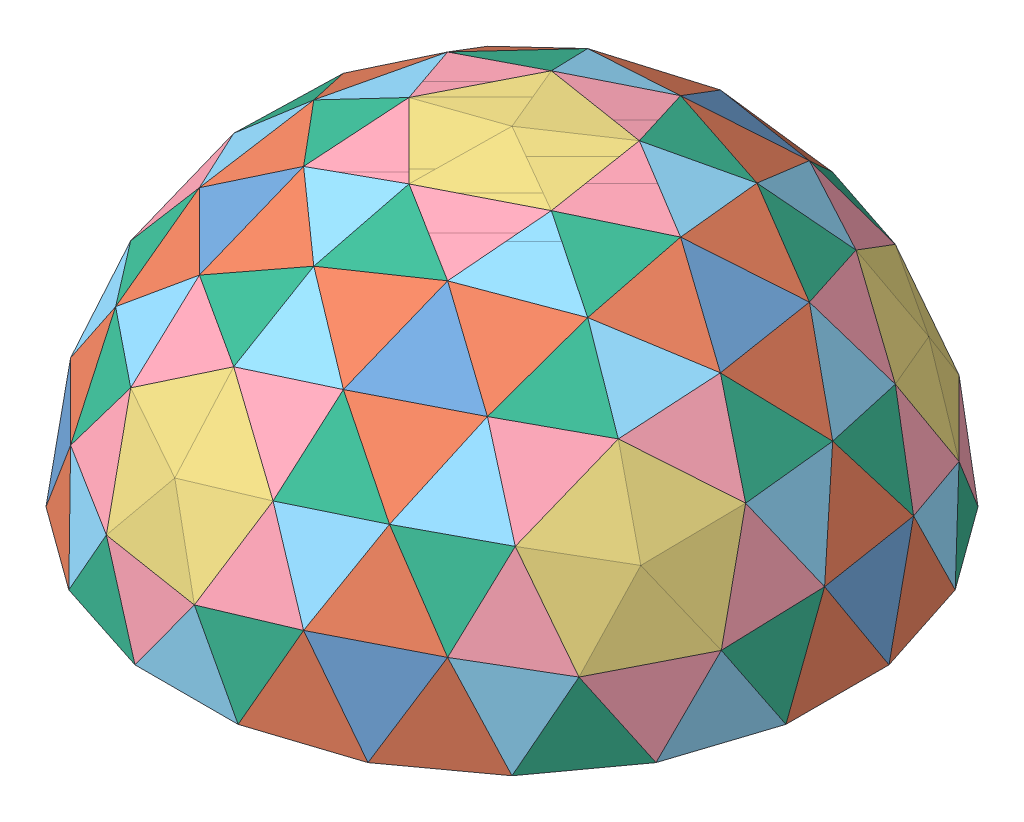
SolidWorks assembly 4Vcorrection, configuration Default. Lengths in mm.
Overall size (6859.98 6146.13 6920.15).
240 component instances, 6 part files, 18 mates.
Components (placement in the parent):
- CCC-1: CCC [Default] at (5148.8544 1241.364 -148.3819) x (0.61992 0.559911 0.549726) z (-0.217119 -0.550832 0.805881) size (730.63 724.53 798.79)
- AAC-1: AAC [Default] at (1003.1437 19.7447 -1471.5178) x (-0.000489 -0.000047 -1) z (0.99533 0.09653 -0.000491) size (938.61 833.05 70.45)
- FFE-1: FFE [Default] at (-5600.516 7252.777 -2822.5483) x (0.186193 0.133009 -0.973469) z (0.267365 0.946545 0.180468) size (827.29 778.64 221.61)
- BBE-1: BBE [Default] at (-5187.0728 4686.9327 1618.959) x (-0.998714 -0.045499 -0.022385) z (0.046496 -0.997846 -0.046278) size (848.33 839.56 282.37)
- ABD-2: ABD [Default] at (-8587.5048 5777.0189 2775.2885) x (-0.624268 -0.021342 0.780919) z (0.059066 -0.998055 0.019942) size (875.61 757.03 437.85)
- ABD_MIRROR-1: ABD_MIRROR [Default] at (1402.3648 4874.5263 -349.4587) x (0.99908 -0.011123 -0.041412) z (0.039506 0.61429 0.788091) size (875.59 747.16 437.21)
- CCC-31: CCC [Default] at (1449.9639 1241.364 -4942.7041) x (0.714386 0.559911 -0.419705) z (0.699345 -0.550832 0.455523) size (730.63 724.53 798.79)
- CCC-32: CCC [Default] at (-4252.7274 1241.364 -2906.3772) x (-0.178406 0.559911 -0.809117) z (0.649338 -0.550832 -0.524352) size (730.63 724.53 798.79)
- CCC-33: CCC [Default] at (-4078.294 1241.364 3146.4642) x (-0.824647 0.559911 -0.080357) z (-0.298032 -0.550832 -0.779591) size (730.63 724.53 798.79)
- CCC-34: CCC [Default] at (1732.2031 1241.364 4850.999) x (-0.331254 0.559911 0.759454) z (-0.833532 -0.550832 0.042538) size (730.63 724.53 798.79)
- AAC-101: AAC [Default] at (1485.5308 -774.2041 604.8619) x (0.385614 -0.797118 0.464656) z (0.921236 0.360604 -0.145909) size (938.61 833.05 70.45)
- AAC-130: AAC [Default] at (1012.6606 1431.4903 312.0988) x (0.060682 0.883368 0.464735) z (0.946767 0.09653 -0.307106) size (938.61 833.05 70.45)
- AAC-131: AAC [Default] at (1611.8244 210.7493 -727.7764) x (0.701451 -0.406472 -0.585445) z (0.543824 0.836189 0.07102) size (938.61 833.05 70.45)
- CCC-26: CCC [Default] at (3250.1059 4014.1834 -1181.8827) x (0.626993 0.22033 -0.747217) z (-0.756223 -0.058225 -0.651719) size (730.63 724.53 798.79)
- AAC-104: AAC [Default] at (-207.4568 1573.9434 -807.289) x (-0.649291 0.632125 -0.422893) z (0.730552 0.672982 -0.115708) size (938.61 833.05 70.45)
- AAC-140: AAC [Default] at (759.5765 1083.2561 1192.3303) x (0.223363 0.139508 0.9647) z (0.495261 0.836189 -0.235595) size (938.61 833.05 70.45)
- AAC-136: AAC [Default] at (609.753 1431.4903 -866.6536) x (0.460741 0.883368 0.085899) z (0.000491 0.09653 -0.99533) size (938.61 833.05 70.45)
- AAC-137: AAC [Default] at (-635.8125 1431.4903 -847.7202) x (0.224072 0.883368 -0.411646) z (-0.946463 0.09653 -0.308041) size (938.61 833.05 70.45)
- AAC-138: AAC [Default] at (-1002.7067 1431.4903 342.7337) x (-0.322257 0.883368 -0.340311) z (-0.585438 0.09653 0.80495) size (938.61 833.05 70.45)
- AAC-139: AAC [Default] at (16.1057 1431.4903 1059.5413) x (-0.423238 0.883368 0.201323) z (0.584643 0.09653 0.805528) size (938.61 833.05 70.45)
- AAC-126: AAC [Default] at (1034.3121 -774.2041 -1225.9111) x (0.561075 -0.797118 -0.223154) z (0.145909 0.360604 -0.921236) size (938.61 833.05 70.45)
- AAC-127: AAC [Default] at (-846.2907 -774.2041 -1362.5167) x (-0.03885 -0.797118 -0.602573) z (-0.831059 0.360604 -0.423446) size (938.61 833.05 70.45)
- AAC-128: AAC [Default] at (-1557.3486 -774.2041 383.8295) x (-0.585086 -0.797118 -0.149256) z (-0.659532 0.360604 0.659532) size (938.61 833.05 70.45)
- AAC-129: AAC [Default] at (-116.2036 -774.2041 1599.7364) x (-0.322753 -0.797118 0.510327) z (0.423446 0.360604 0.831059) size (938.61 833.05 70.45)
- AAC-145: AAC [Default] at (-1089.5081 19.7447 -1408.7704) x (-0.951208 -0.000047 -0.308552) z (0.307106 0.09653 -0.946767) size (938.61 833.05 70.45)
- AAC-146: AAC [Default] at (-1676.4968 19.7447 600.8498) x (-0.587389 -0.000047 0.809304) z (-0.805528 0.09653 -0.584643) size (938.61 833.05 70.45)
- AAC-147: AAC [Default] at (53.3761 19.7447 1780.116) x (0.588181 -0.000047 0.808729) z (-0.80495 0.09653 0.585438) size (938.61 833.05 70.45)
- AAC-148: AAC [Default] at (1709.485 19.7447 499.3224) x (0.950905 -0.000047 -0.309482) z (0.308041 0.09653 0.946463) size (938.61 833.05 70.45)
- AAC-132: AAC [Default] at (-194.0754 210.7493 -1757.8314) x (-0.340031 -0.406472 -0.848032) z (0.235595 0.836189 -0.495261) size (938.61 833.05 70.45)
- AAC-133: AAC [Default] at (-1731.7696 210.7493 -358.6231) x (-0.911602 -0.406472 0.061332) z (-0.398218 0.836189 -0.377108) size (938.61 833.05 70.45)
- AAC-134: AAC [Default] at (-876.2171 210.7493 1536.1901) x (-0.22337 -0.406472 0.885938) z (-0.481707 0.836189 0.262195) size (938.61 833.05 70.45)
- AAC-135: AAC [Default] at (1190.2376 210.7493 1308.0408) x (0.773552 -0.406472 0.486207) z (0.100507 0.836189 0.539154) size (938.61 833.05 70.45)
- CCC-27: CCC [Default] at (-119.6993 4014.1834 -3456.2562) x (-0.516894 0.22033 -0.827209) z (-0.853507 -0.058225 0.517818) size (730.63 724.53 798.79)
- CCC-28: CCC [Default] at (-3324.0841 4014.1834 -954.2011) x (-0.946452 0.22033 0.235974) z (0.228726 -0.058225 0.971748) size (730.63 724.53 798.79)
- CCC-29: CCC [Default] at (-1934.6977 4014.1834 2866.5275) x (-0.068045 0.22033 0.973049) z (0.994868 -0.058225 0.082755) size (730.63 724.53 798.79)
- CCC-30: CCC [Default] at (2128.3752 4014.1834 2725.8125) x (0.904398 0.22033 0.365403) z (0.386136 -0.058225 -0.920603) size (730.63 724.53 798.79)
- AAC-122: AAC [Default] at (-831.8851 1573.9434 -52.1629) x (-0.602838 0.632125 0.486832) z (0.115708 0.672982 -0.730552) size (938.61 833.05 70.45)
- AAC-123: AAC [Default] at (-306.6765 1573.9434 775.0505) x (0.276717 0.632125 0.723772) z (-0.659041 0.672982 -0.335798) size (938.61 833.05 70.45)
- AAC-124: AAC [Default] at (642.3486 1573.9434 531.1705) x (0.773858 0.632125 -0.039516) z (-0.523018 0.672982 0.523018) size (938.61 833.05 70.45)
- AAC-125: AAC [Default] at (703.6698 1573.9434 -446.7691) x (0.201554 0.632125 -0.748194) z (0.335798 0.672982 0.659041) size (938.61 833.05 70.45)
- AAC-141: AAC [Default] at (1368.6955 1083.2561 -353.9498) x (0.986507 0.139508 0.085677) z (-0.07102 0.836189 -0.543824) size (938.61 833.05 70.45)
- AAC-142: AAC [Default] at (86.3239 1083.2561 -1411.0833) x (0.386332 0.139508 -0.911748) z (-0.539154 0.836189 -0.100507) size (938.61 833.05 70.45)
- AAC-143: AAC [Default] at (-1315.3444 1083.2561 -518.1476) x (-0.747741 0.139508 -0.649169) z (-0.262195 0.836189 0.481707) size (938.61 833.05 70.45)
- AAC-144: AAC [Default] at (-899.2515 1083.2561 1090.8505) x (-0.848461 0.139508 0.51054) z (0.377108 0.836189 0.398218) size (938.61 833.05 70.45)
- ABD-53: ABD [Default] at (-14.2287 5777.0189 9024.8137) x (0.549789 -0.021342 0.835031) z (0.037218 -0.998055 -0.050013) size (875.61 757.03 437.85)
- ABD-114: ABD [Default] at (8578.711 5777.0189 2802.3531) x (0.964056 -0.021342 -0.264841) z (-0.036064 -0.998055 -0.050851) size (875.61 757.03 437.85)
- ABD-124: ABD [Default] at (5316.1637 5777.0189 -7292.8643) x (0.04603 -0.021342 -0.998712) z (-0.059507 -0.998055 0.018585) size (875.61 757.03 437.85)
- ABD-134: ABD [Default] at (-5293.1411 5777.0189 -7309.5911) x (-0.935607 -0.021342 -0.352396) z (-0.000713 -0.998055 0.062338) size (875.61 757.03 437.85)
- ABD_MIRROR-37: ABD_MIRROR [Default] at (100.9996 4874.5263 -1441.7169) x (0.269347 -0.011123 -0.962979) z (0.761727 0.61429 0.205961) size (875.59 747.16 437.21)
- ABD_MIRROR-98: ABD_MIRROR [Default] at (-1339.9436 4874.5263 -541.5713) x (-0.832614 -0.011123 -0.553741) z (0.431267 0.61429 -0.660799) size (875.59 747.16 437.21)
- ABD_MIRROR-108: ABD_MIRROR [Default] at (-929.1303 4874.5263 1107.0074) x (-0.783931 -0.011123 0.620748) z (-0.495189 0.61429 -0.614358) size (875.59 747.16 437.21)
- ABD_MIRROR-118: ABD_MIRROR [Default] at (765.7096 4874.5263 1225.7395) x (0.348118 -0.011123 0.937385) z (-0.737311 0.61429 0.281105) size (875.59 747.16 437.21)
- BBE-31: BBE [Default] at (-63.1721 4686.9327 5433.4852) x (-0.329909 -0.045499 0.942916) z (-0.029645 -0.997846 -0.058521) size (848.33 839.56 282.37)
- BBE-92: BBE [Default] at (5148.0302 4686.9327 1739.1195) x (0.794819 -0.045499 0.605139) z (-0.064818 -0.997846 0.01011) size (848.33 839.56 282.37)
- BBE-102: BBE [Default] at (3244.8298 4686.9327 -4358.6502) x (0.821134 -0.045499 -0.568919) z (-0.010415 -0.997846 0.064769) size (848.33 839.56 282.37)
- BBE-112: BBE [Default] at (-3142.6151 4686.9327 -4432.9135) x (-0.28733 -0.045499 -0.95675) z (0.058381 -0.997846 0.02992) size (848.33 839.56 282.37)
- FFE-27: FFE [Default] at (-4415.0576 7252.777 4454.1919) x (-0.868287 0.133009 -0.477898) z (0.254256 0.946545 -0.198512) size (827.29 778.64 221.61)
- FFE-88: FFE [Default] at (2871.8604 7252.777 5575.3903) x (-0.722823 0.133009 0.678111) z (-0.110226 0.946545 -0.303155) size (827.29 778.64 221.61)
- FFE-98: FFE [Default] at (6189.9649 7252.777 -1008.4112) x (0.421558 0.133009 0.896994) z (-0.322379 0.946545 0.011151) size (827.29 778.64 221.61)
- FFE-108: FFE [Default] at (953.7484 7252.777 -6198.6227) x (0.98336 0.133009 -0.123739) z (-0.089015 0.946545 0.310047) size (827.29 778.64 221.61)
- ABD-144: ABD [Default] at (7425.9821 6236.8509 4558.2775) x (0.55211 0.767678 -0.325337) z (0.079677 -0.436992 -0.89593) size (875.61 757.03 437.85)
- ABD_MIRROR-128: ABD_MIRROR [Default] at (-2035.5868 1675.0194 4347.465) x (-0.980472 -0.181349 -0.076077) z (-0.192233 0.965403 0.176194) size (875.59 747.16 437.21)
- BBE-122: BBE [Default] at (4322.8362 4252.0445 3837.6158) x (0.993481 0.099616 0.05542) z (0.097703 -0.493639 -0.864161) size (848.33 839.56 282.37)
- FFE-118: FFE [Default] at (4751.0256 1533.678 8186.0199) x (-0.11914 -0.826546 0.550116) z (-0.411602 0.545327 0.730207) size (827.29 778.64 221.61)
- ABD-78: ABD [Default] at (-1565.091 10558.2109 946.6183) x (-0.610686 0.651209 -0.450545) z (0.107204 -0.495733 -0.861833) size (875.61 757.03 437.85)
- ABD-115: ABD [Default] at (-9510.3268 3858.8763 3079.6379) x (-0.925408 -0.378399 0.020829) z (0.179567 -0.48622 -0.855187) size (875.61 757.03 437.85)
- ABD-125: ABD [Default] at (-5429.6796 -4602.9001 8009.5757) x (0.042879 -0.898262 0.437363) z (0.196762 -0.421599 -0.885177) size (875.61 757.03 437.85)
- ABD-135: ABD [Default] at (5037.5349 -3133.231 8923.4252) x (0.956035 -0.189947 0.22342) z (0.135026 -0.391174 -0.910358) size (875.61 757.03 437.85)
- ABD_MIRROR-62: ABD_MIRROR [Default] at (-658.536 892.1879 4961.8632) x (-0.181899 -0.893371 0.410853) z (-0.854964 0.350088 0.382719) size (875.59 747.16 437.21)
- ABD_MIRROR-99: ABD_MIRROR [Default] at (686.0331 1889.006 4670.2003) x (0.870203 -0.377659 0.316419) z (-0.454945 -0.369384 0.810296) size (875.59 747.16 437.21)
- ABD_MIRROR-109: ABD_MIRROR [Default] at (139.9716 3287.9049 3875.5444) x (0.721865 0.653091 -0.228875) z (0.455011 -0.198728 0.868028) size (875.59 747.16 437.21)
- ABD_MIRROR-119: ABD_MIRROR [Default] at (-1542.082 3155.654 3676.083) x (-0.421915 0.774417 -0.471451) z (0.617376 0.626216 0.47613) size (875.59 747.16 437.21)
- BBE-56: BBE [Default] at (-1057.5495 6904.923 1642.4729) x (0.251277 0.858799 -0.446457) z (0.17386 -0.493801 -0.852017) size (848.33 839.56 282.37)
- BBE-93: BBE [Default] at (-5882.7201 2912.1164 2899.5297) x (-0.829386 0.403031 -0.386892) z (0.202695 -0.42825 -0.880634) size (848.33 839.56 282.37)
- BBE-103: BBE [Default] at (-3484.4538 -2208.4524 5871.5765) x (-0.755068 -0.637832 0.151797) z (0.14436 -0.387575 -0.910465) size (848.33 839.56 282.37)
- BBE-113: BBE [Default] at (2822.9269 -1380.3313 6451.3455) x (0.371526 -0.825352 0.425161) z (0.079471 -0.427987 -0.900284) size (848.33 839.56 282.37)
- FFE-52: FFE [Default] at (2960.0958 7796.1933 4732.0753) x (0.878748 -0.241209 0.41185) z (-0.366301 0.212364 0.905939) size (827.29 778.64 221.61)
- FFE-89: FFE [Default] at (-4324.0091 7767.0971 3593.1159) x (0.636517 0.759674 -0.133195) z (0.002188 0.170919 0.985283) size (827.29 778.64 221.61)
- FFE-99: FFE [Default] at (-7034.9037 1486.5995 6343.1447) x (-0.511078 0.792917 -0.331785) z (0.184626 0.478266 0.858589) size (827.29 778.64 221.61)
- FFE-109: FFE [Default] at (-1426.2239 -2365.8654 9181.7155) x (-0.9781 -0.18742 0.090524) z (-0.07111 0.709663 0.700944) size (827.29 778.64 221.61)
- ABD-149: ABD [Default] at (-14.2287 5777.0189 9024.8137) x (0.549789 -0.021342 0.835031) z (0.037218 -0.998055 -0.050013) size (875.61 757.03 437.85)
- ABD-150: ABD [Default] at (8578.711 5777.0189 2802.3531) x (0.964056 -0.021342 -0.264841) z (-0.036064 -0.998055 -0.050851) size (875.61 757.03 437.85)
- ABD-151: ABD [Default] at (5316.1637 5777.0189 -7292.8643) x (0.04603 -0.021342 -0.998712) z (-0.059507 -0.998055 0.018585) size (875.61 757.03 437.85)
- ABD-152: ABD [Default] at (-5293.1411 5777.0189 -7309.5911) x (-0.935607 -0.021342 -0.352396) z (-0.000713 -0.998055 0.062338) size (875.61 757.03 437.85)
- ABD_MIRROR-133: ABD_MIRROR [Default] at (100.9996 4874.5263 -1441.7169) x (0.269347 -0.011123 -0.962979) z (0.761727 0.61429 0.205961) size (875.59 747.16 437.21)
- ABD_MIRROR-134: ABD_MIRROR [Default] at (-1339.9436 4874.5263 -541.5713) x (-0.832614 -0.011123 -0.553741) z (0.431267 0.61429 -0.660799) size (875.59 747.16 437.21)
- ABD_MIRROR-135: ABD_MIRROR [Default] at (-929.1303 4874.5263 1107.0074) x (-0.783931 -0.011123 0.620748) z (-0.495189 0.61429 -0.614358) size (875.59 747.16 437.21)
- ABD_MIRROR-136: ABD_MIRROR [Default] at (765.7096 4874.5263 1225.7395) x (0.348118 -0.011123 0.937385) z (-0.737311 0.61429 0.281105) size (875.59 747.16 437.21)
- BBE-127: BBE [Default] at (-63.1721 4686.9327 5433.4852) x (-0.329909 -0.045499 0.942916) z (-0.029645 -0.997846 -0.058521) size (848.33 839.56 282.37)
- BBE-128: BBE [Default] at (5148.0302 4686.9327 1739.1195) x (0.794819 -0.045499 0.605139) z (-0.064818 -0.997846 0.01011) size (848.33 839.56 282.37)
- BBE-129: BBE [Default] at (3244.8298 4686.9327 -4358.6502) x (0.821134 -0.045499 -0.568919) z (-0.010415 -0.997846 0.064769) size (848.33 839.56 282.37)
- BBE-130: BBE [Default] at (-3142.6151 4686.9327 -4432.9135) x (-0.28733 -0.045499 -0.95675) z (0.058381 -0.997846 0.02992) size (848.33 839.56 282.37)
- FFE-123: FFE [Default] at (-4415.0576 7252.777 4454.1919) x (-0.868287 0.133009 -0.477898) z (0.254256 0.946545 -0.198512) size (827.29 778.64 221.61)
- FFE-124: FFE [Default] at (2871.8604 7252.777 5575.3903) x (-0.722823 0.133009 0.678111) z (-0.110226 0.946545 -0.303155) size (827.29 778.64 221.61)
- FFE-125: FFE [Default] at (6189.9649 7252.777 -1008.4112) x (0.421558 0.133009 0.896994) z (-0.322379 0.946545 0.011151) size (827.29 778.64 221.61)
- FFE-126: FFE [Default] at (953.7484 7252.777 -6198.6227) x (0.98336 0.133009 -0.123739) z (-0.089015 0.946545 0.310047) size (827.29 778.64 221.61)
- ABD-110: ABD [Default] at (8578.711 5777.0189 2802.3531) x (0.964056 -0.021342 -0.264841) z (-0.036064 -0.998055 -0.050851) size (875.61 757.03 437.85)
- ABD-111: ABD [Default] at (5316.1637 5777.0189 -7292.8643) x (0.04603 -0.021342 -0.998712) z (-0.059507 -0.998055 0.018585) size (875.61 757.03 437.85)
- ABD-112: ABD [Default] at (-5293.1411 5777.0189 -7309.5911) x (-0.935607 -0.021342 -0.352396) z (-0.000713 -0.998055 0.062338) size (875.61 757.03 437.85)
- ABD-113: ABD [Default] at (-8587.5048 5777.0189 2775.2885) x (-0.624268 -0.021342 0.780919) z (0.059066 -0.998055 0.019942) size (875.61 757.03 437.85)
- ABD-120: ABD [Default] at (5316.1637 5777.0189 -7292.8643) x (0.04603 -0.021342 -0.998712) z (-0.059507 -0.998055 0.018585) size (875.61 757.03 437.85)
- ABD-121: ABD [Default] at (-5293.1411 5777.0189 -7309.5911) x (-0.935607 -0.021342 -0.352396) z (-0.000713 -0.998055 0.062338) size (875.61 757.03 437.85)
- ABD-122: ABD [Default] at (-8587.5048 5777.0189 2775.2885) x (-0.624268 -0.021342 0.780919) z (0.059066 -0.998055 0.019942) size (875.61 757.03 437.85)
- ABD-123: ABD [Default] at (-14.2287 5777.0189 9024.8137) x (0.549789 -0.021342 0.835031) z (0.037218 -0.998055 -0.050013) size (875.61 757.03 437.85)
- ABD-130: ABD [Default] at (-5293.1411 5777.0189 -7309.5911) x (-0.935607 -0.021342 -0.352396) z (-0.000713 -0.998055 0.062338) size (875.61 757.03 437.85)
- ABD-131: ABD [Default] at (-8587.5048 5777.0189 2775.2885) x (-0.624268 -0.021342 0.780919) z (0.059066 -0.998055 0.019942) size (875.61 757.03 437.85)
- ABD-132: ABD [Default] at (-14.2287 5777.0189 9024.8137) x (0.549789 -0.021342 0.835031) z (0.037218 -0.998055 -0.050013) size (875.61 757.03 437.85)
- ABD-133: ABD [Default] at (8578.711 5777.0189 2802.3531) x (0.964056 -0.021342 -0.264841) z (-0.036064 -0.998055 -0.050851) size (875.61 757.03 437.85)
- ABD-140: ABD [Default] at (-8587.5048 5777.0189 2775.2885) x (-0.624268 -0.021342 0.780919) z (0.059066 -0.998055 0.019942) size (875.61 757.03 437.85)
- ABD-141: ABD [Default] at (-14.2287 5777.0189 9024.8137) x (0.549789 -0.021342 0.835031) z (0.037218 -0.998055 -0.050013) size (875.61 757.03 437.85)
- ABD-142: ABD [Default] at (8578.711 5777.0189 2802.3531) x (0.964056 -0.021342 -0.264841) z (-0.036064 -0.998055 -0.050851) size (875.61 757.03 437.85)
- ABD-143: ABD [Default] at (5316.1637 5777.0189 -7292.8643) x (0.04603 -0.021342 -0.998712) z (-0.059507 -0.998055 0.018585) size (875.61 757.03 437.85)
- ABD_MIRROR-94: ABD_MIRROR [Default] at (-1339.9436 4874.5263 -541.5713) x (-0.832614 -0.011123 -0.553741) z (0.431267 0.61429 -0.660799) size (875.59 747.16 437.21)
- ABD_MIRROR-95: ABD_MIRROR [Default] at (-929.1303 4874.5263 1107.0074) x (-0.783931 -0.011123 0.620748) z (-0.495189 0.61429 -0.614358) size (875.59 747.16 437.21)
- ABD_MIRROR-96: ABD_MIRROR [Default] at (765.7096 4874.5263 1225.7395) x (0.348118 -0.011123 0.937385) z (-0.737311 0.61429 0.281105) size (875.59 747.16 437.21)
- ABD_MIRROR-97: ABD_MIRROR [Default] at (1402.3648 4874.5263 -349.4587) x (0.99908 -0.011123 -0.041412) z (0.039506 0.61429 0.788091) size (875.59 747.16 437.21)
- ABD_MIRROR-104: ABD_MIRROR [Default] at (-929.1303 4874.5263 1107.0074) x (-0.783931 -0.011123 0.620748) z (-0.495189 0.61429 -0.614358) size (875.59 747.16 437.21)
- ABD_MIRROR-105: ABD_MIRROR [Default] at (765.7096 4874.5263 1225.7395) x (0.348118 -0.011123 0.937385) z (-0.737311 0.61429 0.281105) size (875.59 747.16 437.21)
- ABD_MIRROR-106: ABD_MIRROR [Default] at (1402.3648 4874.5263 -349.4587) x (0.99908 -0.011123 -0.041412) z (0.039506 0.61429 0.788091) size (875.59 747.16 437.21)
- ABD_MIRROR-107: ABD_MIRROR [Default] at (100.9996 4874.5263 -1441.7169) x (0.269347 -0.011123 -0.962979) z (0.761727 0.61429 0.205961) size (875.59 747.16 437.21)
- ABD_MIRROR-114: ABD_MIRROR [Default] at (765.7096 4874.5263 1225.7395) x (0.348118 -0.011123 0.937385) z (-0.737311 0.61429 0.281105) size (875.59 747.16 437.21)
- ABD_MIRROR-115: ABD_MIRROR [Default] at (1402.3648 4874.5263 -349.4587) x (0.99908 -0.011123 -0.041412) z (0.039506 0.61429 0.788091) size (875.59 747.16 437.21)
- ABD_MIRROR-116: ABD_MIRROR [Default] at (100.9996 4874.5263 -1441.7169) x (0.269347 -0.011123 -0.962979) z (0.761727 0.61429 0.205961) size (875.59 747.16 437.21)
- ABD_MIRROR-117: ABD_MIRROR [Default] at (-1339.9436 4874.5263 -541.5713) x (-0.832614 -0.011123 -0.553741) z (0.431267 0.61429 -0.660799) size (875.59 747.16 437.21)
- ABD_MIRROR-124: ABD_MIRROR [Default] at (1402.3648 4874.5263 -349.4587) x (0.99908 -0.011123 -0.041412) z (0.039506 0.61429 0.788091) size (875.59 747.16 437.21)
- ABD_MIRROR-125: ABD_MIRROR [Default] at (100.9996 4874.5263 -1441.7169) x (0.269347 -0.011123 -0.962979) z (0.761727 0.61429 0.205961) size (875.59 747.16 437.21)
- ABD_MIRROR-126: ABD_MIRROR [Default] at (-1339.9436 4874.5263 -541.5713) x (-0.832614 -0.011123 -0.553741) z (0.431267 0.61429 -0.660799) size (875.59 747.16 437.21)
- ABD_MIRROR-127: ABD_MIRROR [Default] at (-929.1303 4874.5263 1107.0074) x (-0.783931 -0.011123 0.620748) z (-0.495189 0.61429 -0.614358) size (875.59 747.16 437.21)
- BBE-88: BBE [Default] at (5148.0302 4686.9327 1739.1195) x (0.794819 -0.045499 0.605139) z (-0.064818 -0.997846 0.01011) size (848.33 839.56 282.37)
- BBE-89: BBE [Default] at (3244.8298 4686.9327 -4358.6502) x (0.821134 -0.045499 -0.568919) z (-0.010415 -0.997846 0.064769) size (848.33 839.56 282.37)
- BBE-90: BBE [Default] at (-3142.6151 4686.9327 -4432.9135) x (-0.28733 -0.045499 -0.95675) z (0.058381 -0.997846 0.02992) size (848.33 839.56 282.37)
- BBE-91: BBE [Default] at (-5187.0728 4686.9327 1618.959) x (-0.998714 -0.045499 -0.022385) z (0.046496 -0.997846 -0.046278) size (848.33 839.56 282.37)
- BBE-98: BBE [Default] at (3244.8298 4686.9327 -4358.6502) x (0.821134 -0.045499 -0.568919) z (-0.010415 -0.997846 0.064769) size (848.33 839.56 282.37)
- BBE-99: BBE [Default] at (-3142.6151 4686.9327 -4432.9135) x (-0.28733 -0.045499 -0.95675) z (0.058381 -0.997846 0.02992) size (848.33 839.56 282.37)
- BBE-100: BBE [Default] at (-5187.0728 4686.9327 1618.959) x (-0.998714 -0.045499 -0.022385) z (0.046496 -0.997846 -0.046278) size (848.33 839.56 282.37)
- BBE-101: BBE [Default] at (-63.1721 4686.9327 5433.4852) x (-0.329909 -0.045499 0.942916) z (-0.029645 -0.997846 -0.058521) size (848.33 839.56 282.37)
- BBE-108: BBE [Default] at (-3142.6151 4686.9327 -4432.9135) x (-0.28733 -0.045499 -0.95675) z (0.058381 -0.997846 0.02992) size (848.33 839.56 282.37)
- BBE-109: BBE [Default] at (-5187.0728 4686.9327 1618.959) x (-0.998714 -0.045499 -0.022385) z (0.046496 -0.997846 -0.046278) size (848.33 839.56 282.37)
- BBE-110: BBE [Default] at (-63.1721 4686.9327 5433.4852) x (-0.329909 -0.045499 0.942916) z (-0.029645 -0.997846 -0.058521) size (848.33 839.56 282.37)
- BBE-111: BBE [Default] at (5148.0302 4686.9327 1739.1195) x (0.794819 -0.045499 0.605139) z (-0.064818 -0.997846 0.01011) size (848.33 839.56 282.37)
- BBE-118: BBE [Default] at (-5187.0728 4686.9327 1618.959) x (-0.998714 -0.045499 -0.022385) z (0.046496 -0.997846 -0.046278) size (848.33 839.56 282.37)
- BBE-119: BBE [Default] at (-63.1721 4686.9327 5433.4852) x (-0.329909 -0.045499 0.942916) z (-0.029645 -0.997846 -0.058521) size (848.33 839.56 282.37)
- BBE-120: BBE [Default] at (5148.0302 4686.9327 1739.1195) x (0.794819 -0.045499 0.605139) z (-0.064818 -0.997846 0.01011) size (848.33 839.56 282.37)
- BBE-121: BBE [Default] at (3244.8298 4686.9327 -4358.6502) x (0.821134 -0.045499 -0.568919) z (-0.010415 -0.997846 0.064769) size (848.33 839.56 282.37)
- FFE-84: FFE [Default] at (2871.8604 7252.777 5575.3903) x (-0.722823 0.133009 0.678111) z (-0.110226 0.946545 -0.303155) size (827.29 778.64 221.61)
- FFE-85: FFE [Default] at (6189.9649 7252.777 -1008.4112) x (0.421558 0.133009 0.896994) z (-0.322379 0.946545 0.011151) size (827.29 778.64 221.61)
- FFE-86: FFE [Default] at (953.7484 7252.777 -6198.6227) x (0.98336 0.133009 -0.123739) z (-0.089015 0.946545 0.310047) size (827.29 778.64 221.61)
- FFE-87: FFE [Default] at (-5600.516 7252.777 -2822.5483) x (0.186193 0.133009 -0.973469) z (0.267365 0.946545 0.180468) size (827.29 778.64 221.61)
- FFE-94: FFE [Default] at (6189.9649 7252.777 -1008.4112) x (0.421558 0.133009 0.896994) z (-0.322379 0.946545 0.011151) size (827.29 778.64 221.61)
- FFE-95: FFE [Default] at (953.7484 7252.777 -6198.6227) x (0.98336 0.133009 -0.123739) z (-0.089015 0.946545 0.310047) size (827.29 778.64 221.61)
- FFE-96: FFE [Default] at (-5600.516 7252.777 -2822.5483) x (0.186193 0.133009 -0.973469) z (0.267365 0.946545 0.180468) size (827.29 778.64 221.61)
- FFE-97: FFE [Default] at (-4415.0576 7252.777 4454.1919) x (-0.868287 0.133009 -0.477898) z (0.254256 0.946545 -0.198512) size (827.29 778.64 221.61)
- FFE-104: FFE [Default] at (953.7484 7252.777 -6198.6227) x (0.98336 0.133009 -0.123739) z (-0.089015 0.946545 0.310047) size (827.29 778.64 221.61)
- FFE-105: FFE [Default] at (-5600.516 7252.777 -2822.5483) x (0.186193 0.133009 -0.973469) z (0.267365 0.946545 0.180468) size (827.29 778.64 221.61)
- FFE-106: FFE [Default] at (-4415.0576 7252.777 4454.1919) x (-0.868287 0.133009 -0.477898) z (0.254256 0.946545 -0.198512) size (827.29 778.64 221.61)
- FFE-107: FFE [Default] at (2871.8604 7252.777 5575.3903) x (-0.722823 0.133009 0.678111) z (-0.110226 0.946545 -0.303155) size (827.29 778.64 221.61)
- FFE-114: FFE [Default] at (-5600.516 7252.777 -2822.5483) x (0.186193 0.133009 -0.973469) z (0.267365 0.946545 0.180468) size (827.29 778.64 221.61)
- FFE-115: FFE [Default] at (-4415.0576 7252.777 4454.1919) x (-0.868287 0.133009 -0.477898) z (0.254256 0.946545 -0.198512) size (827.29 778.64 221.61)
- FFE-116: FFE [Default] at (2871.8604 7252.777 5575.3903) x (-0.722823 0.133009 0.678111) z (-0.110226 0.946545 -0.303155) size (827.29 778.64 221.61)
- FFE-117: FFE [Default] at (6189.9649 7252.777 -1008.4112) x (0.421558 0.133009 0.896994) z (-0.322379 0.946545 0.011151) size (827.29 778.64 221.61)
- ABD-145: ABD [Default] at (6629.9342 6236.8509 -5653.9434) x (-0.138802 0.767678 -0.625623) z (-0.827458 -0.436992 -0.352635) size (875.61 757.03 437.85)
- ABD-146: ABD [Default] at (-3328.4574 6236.8509 -8052.6067) x (-0.637895 0.767678 -0.06132) z (-0.591074 -0.436992 0.67799) size (875.61 757.03 437.85)
- ABD-147: ABD [Default] at (-8687.034 6236.8509 677.1587) x (-0.255439 0.767678 0.587725) z (0.462154 -0.436992 0.771655) size (875.61 757.03 437.85)
- ABD-148: ABD [Default] at (-2040.4249 6236.8509 8471.1139) x (0.480025 0.767678 0.424554) z (0.876701 -0.436992 -0.20108) size (875.61 757.03 437.85)
- ABD_MIRROR-129: ABD_MIRROR [Default] at (3505.654 1675.0194 3279.3986) x (-0.375336 -0.181349 0.908975) z (0.108167 0.965403 0.237271) size (875.59 747.16 437.21)
- ABD_MIRROR-130: ABD_MIRROR [Default] at (4202.2001 1675.0194 -2320.6852) x (0.748501 -0.181349 0.637855) z (0.259084 0.965403 -0.029552) size (875.59 747.16 437.21)
- ABD_MIRROR-131: ABD_MIRROR [Default] at (-908.5515 1675.0194 -4713.6609) x (0.837935 -0.181349 -0.514759) z (0.051956 0.965403 -0.255535) size (875.59 747.16 437.21)
- ABD_MIRROR-132: ABD_MIRROR [Default] at (-4763.7158 1675.0194 -592.5175) x (-0.230628 -0.181349 -0.955993) z (-0.226973 0.965403 -0.128378) size (875.59 747.16 437.21)
- BBE-123: BBE [Default] at (4985.6194 4252.0445 -2925.373) x (0.35971 0.099616 -0.927731) z (-0.791674 -0.493639 -0.359962) size (848.33 839.56 282.37)
- BBE-124: BBE [Default] at (-1241.554 4252.0445 -5645.5958) x (-0.771168 0.099616 -0.628789) z (-0.586985 -0.493639 0.641693) size (848.33 839.56 282.37)
- BBE-125: BBE [Default] at (-5752.9419 4252.0445 -563.797) x (-0.836318 0.099616 0.539118) z (0.428898 -0.493639 0.75655) size (848.33 839.56 282.37)
- BBE-126: BBE [Default] at (-2313.9597 4252.0445 5297.1501) x (0.254295 0.099616 0.961983) z (0.852058 -0.493639 -0.174119) size (848.33 839.56 282.37)
- FFE-119: FFE [Default] at (9253.5152 1533.678 -1988.8746) x (0.486375 -0.826546 0.283304) z (0.567276 0.545327 0.617103) size (827.29 778.64 221.61)
- FFE-120: FFE [Default] at (967.9613 1533.678 -9415.212) x (0.419737 -0.826546 -0.375025) z (0.762198 0.545327 -0.348817) size (827.29 778.64 221.61)
- FFE-121: FFE [Default] at (-8655.2822 1533.678 -3830.0464) x (-0.226964 -0.826546 -0.515082) z (-0.096212 0.545327 -0.832684) size (827.29 778.64 221.61)
- FFE-122: FFE [Default] at (-6317.2199 1533.678 7048.1131) x (-0.560008 -0.826546 0.056686) z (-0.82166 0.545327 -0.16581) size (827.29 778.64 221.61)
- ABD-106: ABD [Default] at (416.6478 10558.2109 1781.0111) x (-0.617206 0.651209 0.441571) z (-0.786524 -0.495733 -0.368278) size (875.61 757.03 437.85)
- ABD-107: ABD [Default] at (1822.5935 10558.2109 154.1071) x (0.229232 0.651209 0.72345) z (-0.593303 -0.495733 0.634224) size (875.61 757.03 437.85)
- ABD-108: ABD [Default] at (709.7769 10558.2109 -1685.7677) x (0.758878 0.651209 0.005546) z (0.419843 -0.495733 0.76025) size (875.61 757.03 437.85)
- ABD-109: ABD [Default] at (-1383.9272 10558.2109 -1195.9688) x (0.239781 0.651209 -0.720022) z (0.852779 -0.495733 -0.164364) size (875.61 757.03 437.85)
- ABD-116: ABD [Default] at (-9.9429 3858.8763 9996.5188) x (-0.266157 -0.378399 0.886552) z (-0.757842 -0.48622 -0.435045) size (875.61 757.03 437.85)
- ABD-117: ABD [Default] at (9504.1818 3858.8763 3098.5505) x (0.760914 -0.378399 0.52709) z (-0.647939 -0.48622 0.586315) size (875.61 757.03 437.85)
- ABD-118: ABD [Default] at (5883.8503 3858.8763 -8081.5093) x (0.736428 -0.378399 -0.560793) z (0.357394 -0.48622 0.797408) size (875.61 757.03 437.85)
- ABD-119: ABD [Default] at (-5867.7623 3858.8763 -8093.1979) x (-0.305777 -0.378399 -0.873679) z (0.868821 -0.48622 -0.093489) size (875.61 757.03 437.85)
- ABD-126: ABD [Default] at (5939.6959 -4602.9001 7639.0272) x (0.429207 -0.898262 0.094372) z (-0.781051 -0.421599 -0.460666) size (875.61 757.03 437.85)
- ABD-127: ABD [Default] at (9100.6136 -4602.9001 -3288.3972) x (0.222386 -0.898262 -0.379037) z (-0.679478 -0.421599 0.60047) size (875.61 757.03 437.85)
- ABD-128: ABD [Default] at (-315.2074 -4602.9001 -9671.3685) x (-0.291765 -0.898262 -0.32863) z (0.361111 -0.421599 0.831777) size (875.61 757.03 437.85)
- ABD-129: ABD [Default] at (-9295.4224 -4602.9001 -2688.8372) x (-0.402706 -0.898262 0.175932) z (0.902656 -0.421599 -0.086403) size (875.61 757.03 437.85)
- ABD-136: ABD [Default] at (10043.3656 -3133.231 -2033.4904) x (0.507916 -0.189947 -0.840203) z (-0.824076 -0.391174 -0.409734) size (875.61 757.03 437.85)
- ABD-137: ABD [Default] at (1169.6064 -3133.231 -10180.1914) x (-0.642126 -0.189947 -0.742694) z (-0.644333 -0.391174 0.657128) size (875.61 757.03 437.85)
- ABD-138: ABD [Default] at (-9320.5091 -3133.231 -4258.2139) x (-0.904772 -0.189947 0.381193) z (0.425856 -0.391174 0.815861) size (875.61 757.03 437.85)
- ABD-139: ABD [Default] at (-6929.9978 -3133.231 7548.4705) x (0.082946 -0.189947 0.978284) z (0.907527 -0.391174 -0.152898) size (875.61 757.03 437.85)
- ABD_MIRROR-90: ABD_MIRROR [Default] at (4515.5135 892.1879 2159.605) x (0.334534 -0.893371 0.299957) z (0.099789 0.350088 0.931386) size (875.59 747.16 437.21)
- ABD_MIRROR-91: ABD_MIRROR [Default] at (3449.2768 892.1879 -3627.1539) x (0.388653 -0.893371 -0.225469) z (0.916638 0.350088 0.192909) size (875.59 747.16 437.21)
- ABD_MIRROR-92: ABD_MIRROR [Default] at (-2383.7432 892.1879 -4401.3094) x (-0.094334 -0.893371 -0.439305) z (0.466724 0.350088 -0.812162) size (875.59 747.16 437.21)
- ABD_MIRROR-93: ABD_MIRROR [Default] at (-4922.5111 892.1879 906.9951) x (-0.446954 -0.893371 -0.046036) z (-0.628186 0.350088 -0.694853) size (875.59 747.16 437.21)
- ABD_MIRROR-100: ABD_MIRROR [Default] at (4653.6203 1889.006 790.715) x (0.56984 -0.377659 -0.729833) z (0.630052 -0.369384 0.683074) size (875.59 747.16 437.21)
- ABD_MIRROR-101: ABD_MIRROR [Default] at (2190.0624 1889.006 -4181.5115) x (-0.518022 -0.377659 -0.767481) z (0.844339 -0.369384 -0.388134) size (875.59 747.16 437.21)
- ABD_MIRROR-102: ABD_MIRROR [Default] at (-3300.0872 1889.006 -3375.0313) x (-0.889995 -0.377659 0.255504) z (-0.108222 -0.369384 -0.922954) size (875.59 747.16 437.21)
- ABD_MIRROR-103: ABD_MIRROR [Default] at (-4229.6285 1889.006 2095.6275) x (-0.032025 -0.377659 0.925391) z (-0.911224 -0.369384 -0.182283) size (875.59 747.16 437.21)
- ABD_MIRROR-110: ABD_MIRROR [Default] at (3729.1154 3287.9049 1064.4882) x (0.005396 0.653091 -0.75726) z (0.96615 -0.198728 -0.164506) size (875.59 747.16 437.21)
- ABD_MIRROR-111: ABD_MIRROR [Default] at (2164.7485 3287.9049 -3217.6545) x (-0.71853 0.653091 -0.239138) z (0.142102 -0.198728 -0.969698) size (875.59 747.16 437.21)
- ABD_MIRROR-112: ABD_MIRROR [Default] at (-2391.2272 3287.9049 -3053.1081) x (-0.449472 0.653091 0.609465) z (-0.878326 -0.198728 -0.4348) size (875.59 747.16 437.21)
- ABD_MIRROR-113: ABD_MIRROR [Default] at (-3642.6082 3287.9049 1330.73) x (0.440741 0.653091 0.615808) z (-0.684937 -0.198728 0.700977) size (875.59 747.16 437.21)
- ABD_MIRROR-120: ABD_MIRROR [Default] at (3019.6332 3155.654 2602.5793) x (-0.578755 0.774417 0.255579) z (0.643607 0.626216 -0.440027) size (875.59 747.16 437.21)
- ABD_MIRROR-121: ABD_MIRROR [Default] at (3408.3179 3155.654 -2067.6006) x (0.064224 0.774417 0.629407) z (-0.219605 0.626216 -0.748082) size (875.59 747.16 437.21)
- ABD_MIRROR-122: ABD_MIRROR [Default] at (-913.1769 3155.654 -3880.4267) x (0.618448 0.774417 0.133416) z (-0.77933 0.626216 -0.022313) size (875.59 747.16 437.21)
- ABD_MIRROR-123: ABD_MIRROR [Default] at (-3972.6923 3155.654 -330.635) x (0.317997 0.774417 -0.546951) z (-0.262047 0.626216 0.734292) size (875.59 747.16 437.21)
- BBE-84: BBE [Default] at (1235.2838 6904.923 1513.3414) x (-0.346957 0.858799 -0.376942) z (-0.756591 -0.493801 -0.428638) size (848.33 839.56 282.37)
- BBE-85: BBE [Default] at (1820.9969 6904.923 -707.1765) x (-0.465708 0.858799 0.213494) z (-0.641459 -0.493801 0.587104) size (848.33 839.56 282.37)
- BBE-86: BBE [Default] at (-109.8458 6904.923 -1950.4005) x (0.059133 0.858799 0.508888) z (0.360148 -0.493801 0.791489) size (848.33 839.56 282.37)
- BBE-87: BBE [Default] at (-1888.8854 6904.923 -498.2373) x (0.502255 0.858799 0.101016) z (0.864042 -0.493801 -0.097937) size (848.33 839.56 282.37)
- BBE-94: BBE [Default] at (939.7562 2912.1164 6490.8032) x (-0.624251 0.403031 0.669236) z (-0.774897 -0.42825 -0.464906) size (848.33 839.56 282.37)
- BBE-95: BBE [Default] at (6463.5213 2912.1164 1112.0073) x (0.443578 0.403031 0.800503) z (-0.681608 -0.42825 0.593307) size (848.33 839.56 282.37)
- BBE-96: BBE [Default] at (3054.9197 2912.1164 -5803.5449) x (0.898397 0.403031 -0.174498) z (0.35364 -0.42825 0.831589) size (848.33 839.56 282.37)
- BBE-97: BBE [Default] at (-4575.4771 2912.1164 -4698.7953) x (0.111662 0.403031 -0.908349) z (0.900169 -0.42825 -0.079356) size (848.33 839.56 282.37)
- BBE-104: BBE [Default] at (4507.4456 -2208.4524 5128.3294) x (-0.088961 -0.637832 0.76502) z (-0.821294 -0.387575 -0.418643) size (848.33 839.56 282.37)
- BBE-105: BBE [Default] at (6270.2084 -2208.4524 -2702.0946) x (0.700087 -0.637832 0.321011) z (-0.651947 -0.387575 0.651729) size (848.33 839.56 282.37)
- BBE-106: BBE [Default] at (-632.2437 -2208.4524 -6798.3157) x (0.521639 -0.637832 -0.566625) z (0.418368 -0.387575 0.821434) size (848.33 839.56 282.37)
- BBE-107: BBE [Default] at (-6660.9565 -2208.4524 -1499.4956) x (-0.377697 -0.637832 -0.671205) z (0.910513 -0.387575 -0.144055) size (848.33 839.56 282.37)
- BBE-114: BBE [Default] at (7007.9266 -1380.3313 -691.1876) x (0.51916 -0.825352 -0.22196) z (-0.831663 -0.427987 -0.353785) size (848.33 839.56 282.37)
- BBE-115: BBE [Default] at (1508.2099 -1380.3313 -6878.523) x (-0.050667 -0.825352 -0.56234) z (-0.593467 -0.427987 0.681633) size (848.33 839.56 282.37)
- BBE-116: BBE [Default] at (-6075.8016 -1380.3313 -3559.9734) x (-0.550474 -0.825352 -0.125585) z (0.46488 -0.427987 0.775057) size (848.33 839.56 282.37)
- BBE-117: BBE [Default] at (-5263.2618 -1380.3313 4678.3384) x (-0.289545 -0.825352 0.484724) z (0.880779 -0.427987 -0.202622) size (848.33 839.56 282.37)
- FFE-80: FFE [Default] at (5415.191 7796.1933 -1352.9267) x (0.66324 -0.241209 -0.70847) z (0.748406 0.212364 0.628324) size (827.29 778.64 221.61)
- FFE-81: FFE [Default] at (386.6762 7796.1933 -5568.23) x (-0.468843 -0.241209 -0.849709) z (0.828841 0.212364 -0.517613) size (827.29 778.64 221.61)
- FFE-82: FFE [Default] at (-5176.2119 7796.1933 -2088.4287) x (-0.953001 -0.241209 0.183322) z (-0.236153 0.212364 -0.948226) size (827.29 778.64 221.61)
- FFE-83: FFE [Default] at (-3585.7511 7796.1933 4277.5101) x (-0.120144 -0.241209 0.963008) z (-0.974792 0.212364 -0.068423) size (827.29 778.64 221.61)
- FFE-90: FFE [Default] at (2081.064 7767.0971 5222.7109) x (0.070018 0.759674 -0.646523) z (0.937736 0.170919 0.302388) size (827.29 778.64 221.61)
- FFE-91: FFE [Default] at (5610.1773 7767.0971 -365.303) x (-0.593244 0.759674 -0.266378) z (0.577365 0.170919 -0.798397) size (827.29 778.64 221.61)
- FFE-92: FFE [Default] at (1386.2163 7767.0971 -5448.4806) x (-0.436663 0.759674 0.481893) z (-0.580905 0.170919 -0.795824) size (827.29 778.64 221.61)
- FFE-93: FFE [Default] at (-4753.4485 7767.0971 -3002.0431) x (0.323371 0.759674 0.564204) z (-0.936383 0.170919 0.30655) size (827.29 778.64 221.61)
- FFE-100: FFE [Default] at (3858.7843 1486.5995 8650.7306) x (-0.473478 0.792917 0.383537) z (0.873619 0.478266 0.089729) size (827.29 778.64 221.61)
- FFE-101: FFE [Default] at (9419.7636 1486.5995 -996.6992) x (0.218452 0.792917 0.568824) z (0.3553 0.478266 -0.803133) size (827.29 778.64 221.61)
- FFE-102: FFE [Default] at (1962.9497 1486.5995 -9266.7246) x (0.608489 0.792917 -0.031984) z (-0.654031 0.478266 -0.586092) size (827.29 778.64 221.61)
- FFE-103: FFE [Default] at (-8206.5939 1486.5995 -4730.4515) x (0.157615 0.792917 -0.588591) z (-0.759514 0.478266 0.440908) size (827.29 778.64 221.61)
- FFE-110: FFE [Default] at (8291.603 -2365.8654 4193.7256) x (-0.216156 -0.18742 0.958202) z (0.644663 0.709663 0.284233) size (827.29 778.64 221.61)
- FFE-111: FFE [Default] at (6550.7163 -2365.8654 -6589.8506) x (0.844508 -0.18742 0.501677) z (0.469534 0.709663 -0.525278) size (827.29 778.64 221.61)
- FFE-112: FFE [Default] at (-4243.0376 -2365.8654 -8266.4772) x (0.73809 -0.18742 -0.648148) z (-0.354475 0.709663 -0.608873) size (827.29 778.64 221.61)
- FFE-113: FFE [Default] at (-9173.0578 -2365.8654 1480.8866) x (-0.388343 -0.18742 -0.902254) z (-0.688611 0.709663 0.148974) size (827.29 778.64 221.61)
Mates (geometry in assembly coordinates):
- Coincident105: coincident: point of assembly; point of AAC-1; line of assembly
- Coincident106: coincident: point of assembly; point of assembly; point of AAC-1; point of assembly
- Coincident108: coincident: point of assembly; point of assembly; point of assembly; point of AAC-1
- Coincident109: coincident: point of assembly; point of AAC-1; point of assembly
- Coincident110: coincident: point of assembly; point of AAC-1; point of assembly
- Coincident111: coincident: point of assembly; point of AAC-1; point of assembly
- Coincident112: coincident: unknown of ?
- Coincident113: coincident: unknown of ?
- Coincident114: coincident: unknown of ?
- Coincident115: coincident: unknown of ?
- Coincident116: coincident: unknown of ?
- Coincident117: coincident: unknown of ?
- Coincident118: coincident: unknown of ?
- Coincident119: coincident: unknown of ?
- Coincident120: coincident: unknown of ?
- Coincident121: coincident: unknown of ?
- Coincident122: coincident: unknown of ?
- Coincident123: coincident: unknown of ?
